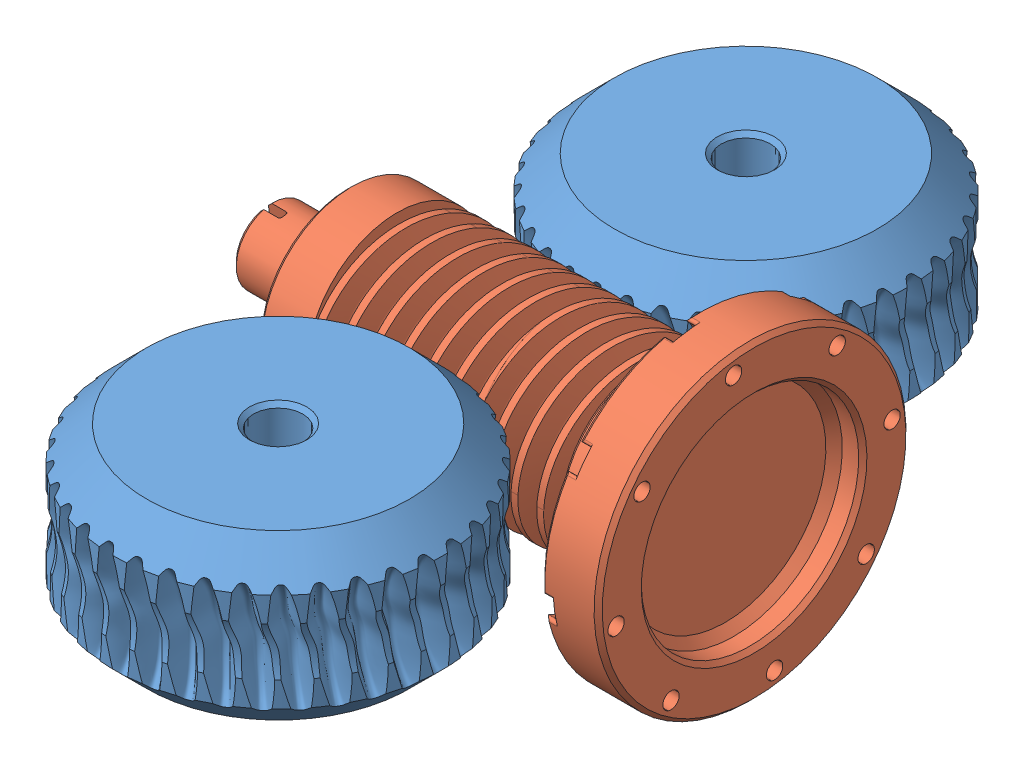
SolidWorks assembly 装配体1, configuration 默认. Lengths in mm.
Overall size (59.1 43.17 105.94).
3 component instances, 2 part files, 9 mates.
Components (placement in the parent):
- 蜗轮导出-1: 蜗轮导出 [默认] at (0 0 28.5) x (0.999995 0 -0.003284) z (0 -1 0) size (43.53 43.51 20)
- 蜗轮导出-2: 蜗轮导出 [默认] at (0 0 -28.5) x (0.957426 0 -0.288679) z (0 -1 0) size (43.53 43.51 20)
- 蜗杆导出-1: 蜗杆导出 [默认] at (6 0 0) x (0 -0.989145 -0.146941) z (0 0.146941 -0.989145) size (38 59.1 38)
Mates (geometry in assembly coordinates):
- 同心1: concentric: cylinder of 蜗轮导出-1 through (0 -10 28.5) axis (0 1 0) radius 3
- 平行1: parallel aligned: plane of 蜗轮导出-1 through (0 10 28.5) normal (0 1 0)
- 距离1: distance = 10 mm: plane of 蜗轮导出-1 through (0 10 28.5) normal (0 1 0)
- 同心2: concentric: cylinder of 蜗轮导出-2 through (0 -10 -28.5) axis (0 1 0) radius 3
- 重合1: coincident aligned: plane of 蜗轮导出-1 through (0 10 28.5) normal (0 1 0); plane of 蜗轮导出-2 through (0 10 -28.5) normal (0 1 0)
- 同心3: concentric aligned: cylinder of 蜗杆导出-1 through (-29.6 0 0) axis (1 0 0) radius 4.5
- 距离2: distance = 20 mm: cylinder of 蜗轮导出-2 through (0 -10 -28.5) axis (0 1 0) radius 3; plane of 蜗杆导出-1 through (-20 0 0) normal (-1 0 0)
- 齿轮配合1: gear = 2 : 37 mm: cylinder of 蜗轮导出-2 through (0 -10 -28.5) axis (0 1 0) radius 20; cylinder of 蜗杆导出-1 through (24 10.124 13.6567) axis (-1 0 0) radius 2.05
- 齿轮配合2: gear = 40 : 40 mm: cylinder of 蜗轮导出-1 through (0 -10 28.5) axis (0 1 0) radius 20; cylinder of 蜗轮导出-2 through (0 -10 -28.5) axis (0 1 0) radius 20
